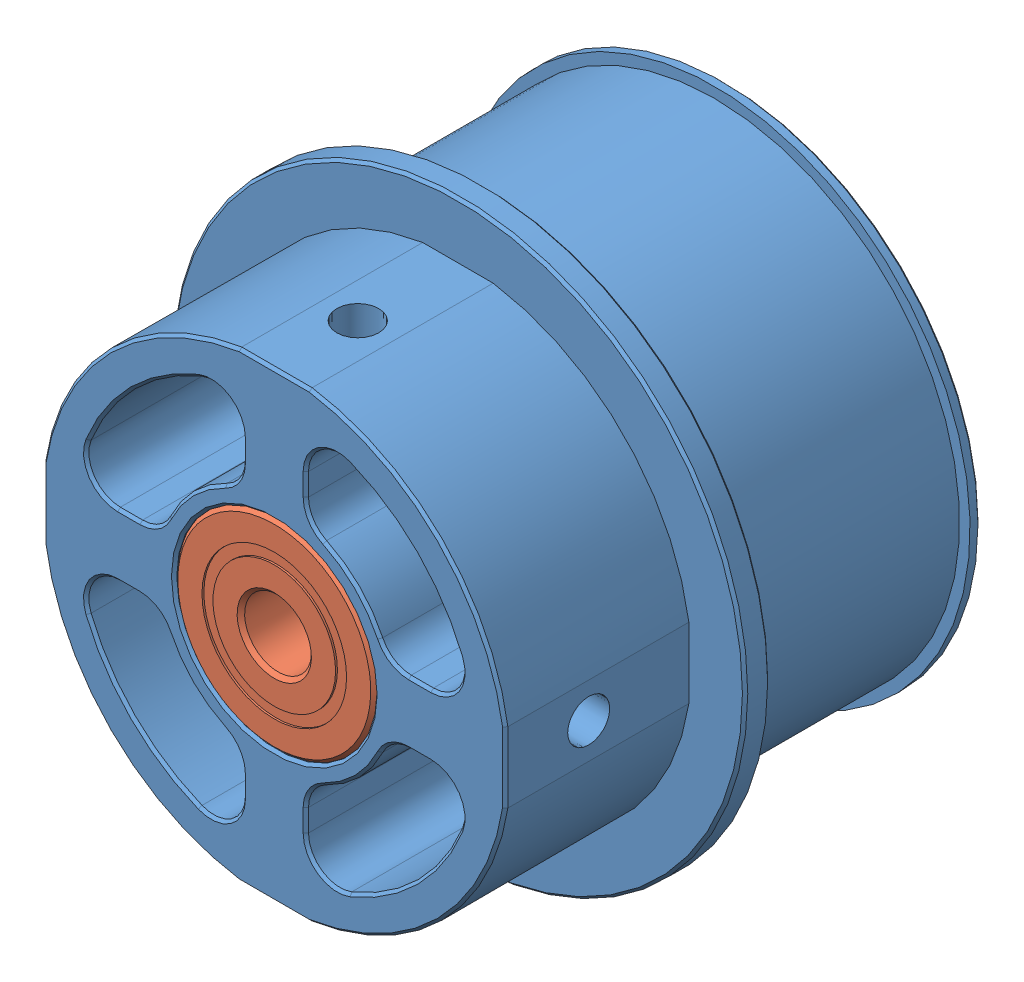
SolidWorks assembly 599-23-OFFSEASON-IN-A-2300, configuration Default. Lengths in mm.
Overall size (54.61 54.61 42.86).
4 component instances, 3 part files, 6 mates.
Components (placement in the parent):
- 599-23-OFFSEASON-IN-P-2104-3: 599-23-OFFSEASON-IN-P-2104 [Default] at (19.9033 29.3467 33.6723) size (54.61 54.61 42.86)
- TTB-0038_75OD_25ID_28WD-1: TTB-0038_75OD_25ID_28WD [Default] at (19.9033 29.3467 22.8442) x (0.920962 -0.389652 0) z (0 0 1) size (19.05 19.05 7.14)
- TTB-0038_75OD_25ID_28WD-2: TTB-0038_75OD_25ID_28WD [Default] at (19.9033 29.3467 58.5629) x (0.992812 0.119685 0) z (0 0 1) size (19.05 19.05 7.14)
- 599-23-OFFSEASON-IN-P-2103-1: 599-23-OFFSEASON-IN-P-2103 [Default] at (19.9033 29.3467 40.7973) x (0.999827 -0.018617 0) z (-0.018617 -0.999827 0) size (9.53 28.76 9.53)
Mates (geometry in assembly coordinates):
- Concentric1: concentric anti-aligned: cylinder of 599-23-OFFSEASON-IN-P-2104-3 through (19.9033 29.3467 62.1348) axis (0 0 -1) radius 9.525; cylinder of TTB-0038_75OD_25ID_28WD-1 through (19.9033 29.3467 26.416) axis (0 0 1) radius 9.525
- Concentric2: concentric aligned: cylinder of 599-23-OFFSEASON-IN-P-2104-3 through (19.9033 29.3467 54.991) axis (0 0 1) radius 9.525; cylinder of TTB-0038_75OD_25ID_28WD-2 through (19.9033 29.3467 62.1348) axis (0 0 1) radius 9.525
- Coincident1: coincident anti-aligned: plane of 599-23-OFFSEASON-IN-P-2104-3 through (19.9033 29.3467 26.416) normal (0 0 -1); plane of TTB-0038_75OD_25ID_28WD-1 through (23.4755 37.7899 26.416) normal (0 0 1)
- Coincident2: coincident anti-aligned: plane of 599-23-OFFSEASON-IN-P-2104-3 through (19.9033 29.3467 54.991) normal (0 0 1); plane of TTB-0038_75OD_25ID_28WD-2 through (18.806 38.4487 54.991) normal (0 0 -1)
- Concentric3: concentric anti-aligned: cylinder of TTB-0038_75OD_25ID_28WD-2 through (19.9033 29.3467 62.1348) axis (0 0 1) radius 3.175; cylinder of 599-23-OFFSEASON-IN-P-2103-1 through (19.9033 29.3467 55.1785) axis (0 0 -1) radius 4.7625
- Coincident3: coincident anti-aligned: plane of TTB-0038_75OD_25ID_28WD-1 through (22.1736 34.7129 26.416) normal (0 0 1); plane of 599-23-OFFSEASON-IN-P-2103-1 through (19.9033 29.3467 26.416) normal (0 0 -1)
